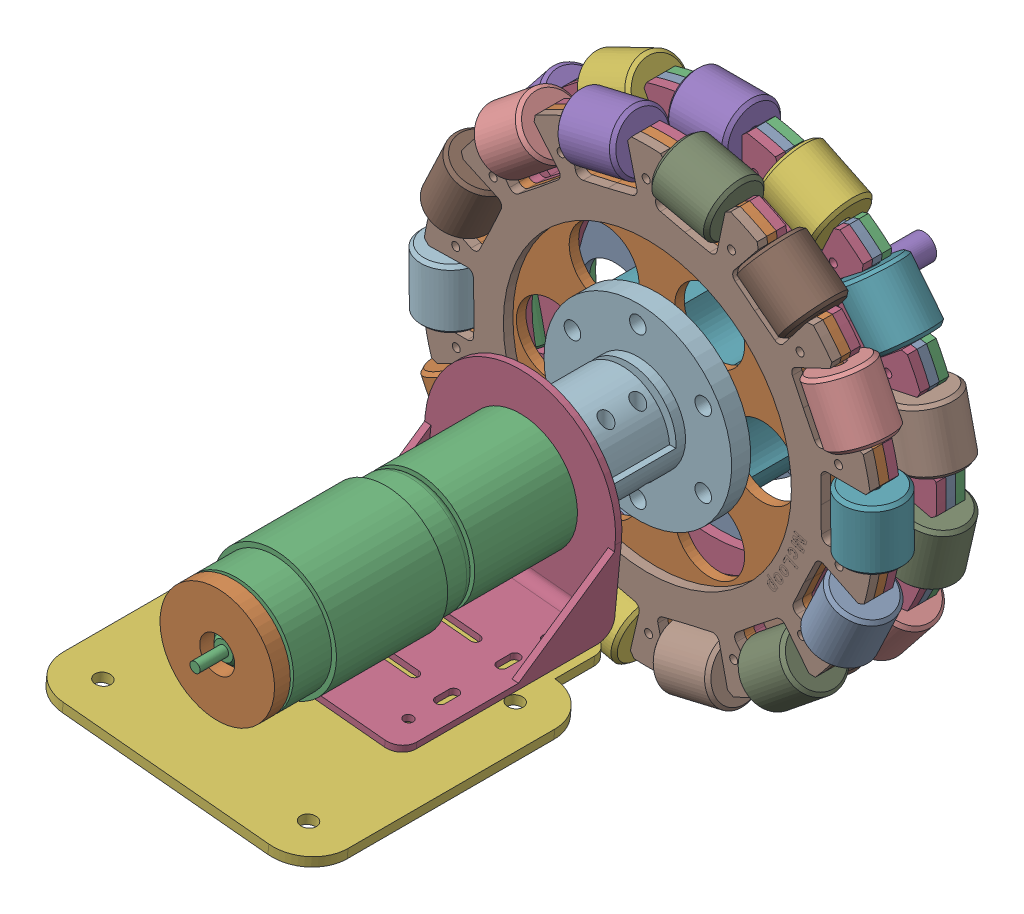
SolidWorks assembly omniWheel, configuration Default. Lengths in mm.
Overall size (151.3 151.2 235.8).
7 component instances, 6 part files, 21 mates.
Components (placement in the parent):
- Omni Wheel 152mm-1: Omni Wheel 152mm [Default] at (29.5619 54.1477 34.7754) size (151.3 151.2 38.6)
- Anti-Slip Coupling 10id-1: Anti-Slip Coupling 10id [Default] at (29.5619 54.3977 69.5254) size (59 59 31)
- Anti-Slip Coupling 10id-2: Anti-Slip Coupling 10id [Default] at (29.5619 54.3977 46.5254) x (1 0 0) z (0 0 -1) size (59 59 31)
- dc motor pg36555126000.step_new-1: dc motor pg36555126000.step_new [Default] at (29.5619 54.3977 157.1754) x (0 0 -1) z (0.995285 -0.096992 0) size (123.6 39 39)
- Motor Mounting Bracket-1: Motor Mounting Bracket [Default] at (26.9431 27.525 110.5254) x (0 0 1) z (0.096992 0.995285 0) size (66.93 60 57)
- shaft8mm-1: shaft8mm [Default] at (29.5619 54.3977 -14.4746) x (-0.886056 -0.463577 0) z (0 0 1) size (8 8 50)
- motorPlate2-1: motorPlate2 [Default] at (26.9431 27.525 176.3254) x (0.995285 -0.096992 0) z (-0.096992 -0.995285 0) size (90 107.5 3)
Mates (geometry in assembly coordinates):
- Concentric1: concentric aligned: cylinder of Omni Wheel 152mm-1 through (29.5619 54.3977 49.5254) axis (0 0 1) radius 11; cylinder of Anti-Slip Coupling-1 through (29.5619 54.3977 69.5254) axis (0 0 1) radius 4
- Concentric2: concentric aligned: cylinder of Omni Wheel 152mm-1 through (29.5619 78.1477 46.5254) axis (0 0 1) radius 2.5; cylinder of Anti-Slip Coupling-1 through (29.5619 78.1477 69.5254) axis (0 0 1) radius 2.6
- Concentric3: concentric aligned: cylinder of Omni Wheel 152mm-1 through (50.13 42.5227 46.5254) axis (0 0 1) radius 2.5; cylinder of Anti-Slip Coupling-1 through (50.13 42.5227 69.5254) axis (0 0 1) radius 2.6
- Coincident1: coincident anti-aligned: plane of Omni Wheel 152mm-1 through (29.5619 54.3977 69.5254) normal (0 0 1); plane of Anti-Slip Coupling-1 through (29.5619 54.3977 69.5254) normal (0 0 -1)
- Concentric4: concentric anti-aligned: cylinder of Omni Wheel 152mm-1 through (29.5619 54.3977 49.5254) axis (0 0 1) radius 11; cylinder of Anti-Slip Coupling-2 through (29.5619 54.3977 46.5254) axis (0 0 -1) radius 4
- Concentric5: concentric anti-aligned: cylinder of Omni Wheel 152mm-1 through (8.9938 66.2727 46.5254) axis (0 0 1) radius 2.5; cylinder of Anti-Slip Coupling-2 through (8.9938 66.2727 46.5254) axis (0 0 -1) radius 2.6
- Concentric6: concentric anti-aligned: cylinder of Omni Wheel 152mm-1 through (29.5619 78.1477 46.5254) axis (0 0 1) radius 2.5; cylinder of Anti-Slip Coupling-2 through (29.5619 78.1477 46.5254) axis (0 0 -1) radius 2.6
- Coincident2: coincident anti-aligned: plane of Omni Wheel 152mm-1 through (29.5619 54.3977 46.5254) normal (0 0 -1); plane of Anti-Slip Coupling-2 through (29.5619 54.3977 46.5254) normal (0 0 1)
- Concentric7: concentric anti-aligned: cylinder of Anti-Slip Coupling-1 through (29.5619 54.3977 69.5254) axis (0 0 1) radius 4; cylinder of dc motor pg36555126000.step_new-1 through (29.5619 54.3977 112.5254) axis (0 0 -1) radius 4
- Concentric8: concentric aligned: cylinder of Anti-Slip Coupling-1 through (29.5619 54.3977 69.5254) axis (0 0 1) radius 4; cylinder of Motor Mounting Bracket-1 through (29.5619 54.3977 110.5254) axis (0 0 1) radius 11
- Concentric9: concentric aligned: cylinder of dc motor pg36555126000.step_new-1 through (40.3749 63.2904 112.5254) axis (0 0 1) radius 1.5; cylinder of Motor Mounting Bracket-1 through (40.3749 63.2904 110.5254) axis (0 0 1) radius 1.65
- Concentric10: concentric aligned: cylinder of dc motor pg36555126000.step_new-1 through (20.6693 65.2107 112.5254) axis (0 0 1) radius 1.5; cylinder of Motor Mounting Bracket-1 through (20.6693 65.2107 110.5254) axis (0 0 1) radius 1.65
- Coincident3: coincident anti-aligned: plane of dc motor pg36555126000.step_new-1 through (47.4771 52.6518 112.5254) normal (0 0 -1); plane of Motor Mounting Bracket-1 through (29.7074 55.8906 112.5254) normal (0 0 1)
- Concentric11: concentric aligned: cylinder of Anti-Slip Coupling-2 through (29.5619 54.3977 46.5254) axis (0 0 -1) radius 4; cylinder of shaft8mm-1 through (29.5619 54.3977 35.5254) axis (0 0 -1) radius 4
- Distance2: distance = 30 mm aligned: plane of Anti-Slip Coupling-2 through (29.5619 54.3977 15.5254) normal (0 0 -1); plane of shaft8mm-1 through (29.5619 54.3977 -14.4746) normal (0 0 -1)
- Distance3: distance = 10 mm anti-aligned: plane of Anti-Slip Coupling-1 through (29.5619 54.3977 100.5254) normal (0 0 1); plane of Motor Mounting Bracket-1 through (29.7074 55.8906 110.5254) normal (0 0 -1)
- Concentric15: concentric aligned: cylinder of Motor Mounting Bracket-1 through (49.8347 25.2942 124.5254) axis (0.096992 0.995285 0) radius 1.5; cylinder of motorPlate2-1 through (49.5437 22.3083 124.5254) axis (0.096992 0.995285 0) radius 1.5
- Concentric16: concentric aligned: cylinder of Motor Mounting Bracket-1 through (4.0516 29.7558 124.5254) axis (0.096992 0.995285 0) radius 1.5; cylinder of motorPlate2-1 through (3.7606 26.77 124.5254) axis (0.096992 0.995285 0) radius 1.5
- Concentric17: concentric aligned: cylinder of Motor Mounting Bracket-1 through (4.0516 29.7558 168.1254) axis (0.096992 0.995285 0) radius 1.5; cylinder of motorPlate2-1 through (3.7606 26.77 168.1254) axis (0.096992 0.995285 0) radius 1.5
- Concentric18: concentric aligned: cylinder of Motor Mounting Bracket-1 through (49.8347 25.2942 168.1254) axis (0.096992 0.995285 0) radius 1.5; cylinder of motorPlate2-1 through (49.5437 22.3083 168.1254) axis (0.096992 0.995285 0) radius 1.5
- Coincident4: coincident anti-aligned: plane of Motor Mounting Bracket-1 through (-2.9154 30.4348 110.5254) normal (-0.096992 -0.995285 0); plane of motorPlate2-1 through (54.3135 24.8577 118.8254) normal (0.096992 0.995285 0)
